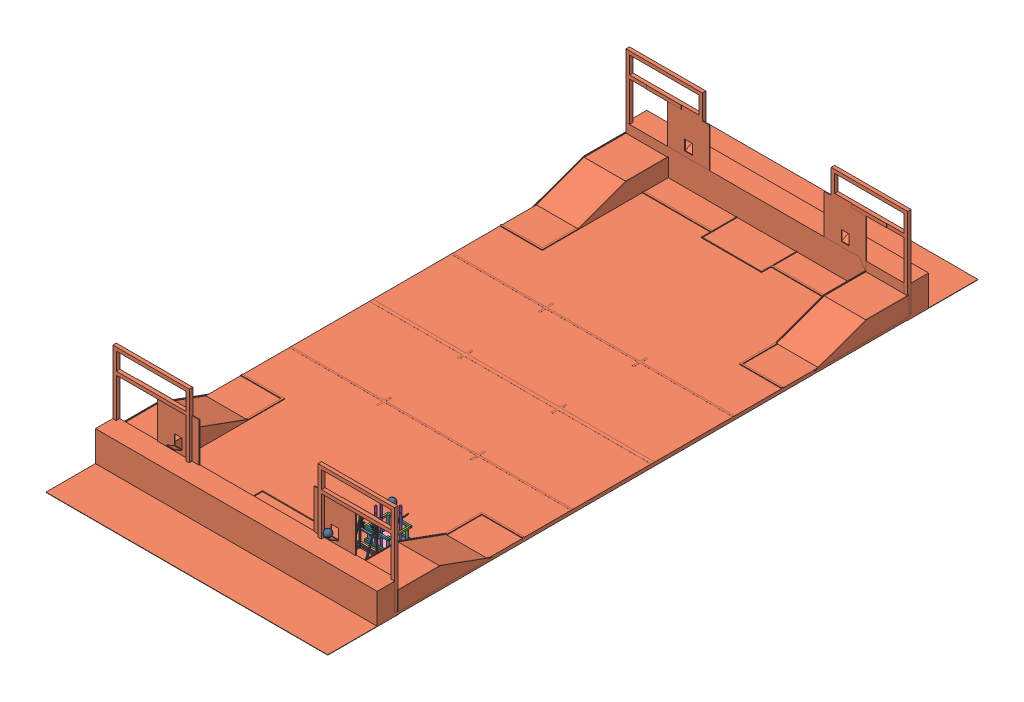
SolidWorks assembly Field, configuration Default. Lengths in mm.
Overall size (8136 2710 18688.65).
71 component instances, 20 part files, 5 mates.
Components (placement in the parent):
- Frame-1: Frame [Default] at (2713.2899 442.2211 10367.8073) x (1 0 0) z (0 -0.012665 0.99992) size (953.99 1281.22 1971.68)
  - User Library-C channel_-1: User Library-C channel_ [Default] at (-264.0117 419.6304 601.8198) size (760 31.75 28.57)
  - User Library-C channel_-2: User Library-C channel_ [Default] at (612.1433 419.6304 689.3998) x (0 0 -1) z (1 0 0) size (760 31.75 28.57)
  - User Library-C channel_-3: User Library-C channel_ [Default] at (463.4933 436.9764 689.3998) x (0 0 -1) z (-1 0 0) size (760 31.75 28.57)
  - User Library-C channel_-4: User Library-C channel_ [Default] at (-154.2067 419.6304 -296.5602) x (0 0 1) z (-1 0 0) size (760 31.75 28.57)
  - User Library-C channel_-5: User Library-C channel_ [Default] at (721.9484 419.6304 -208.9802) x (-1 0 0) z (0 0 -1) size (760 31.75 28.57)
  - User Library-C channel_-6: User Library-C channel_ [Default] at (-5.5567 419.6304 689.3998) x (0 0 -1) z (1 0 0) size (760 31.75 28.57)
  - Bumper-1: Bumper [Default] at (445.2766 -8.8291 392.6865) x (-1 0 0) z (0 0 -1) size (760 148.52 90.64)
    - Wood-1: Wood [Default] at (216.3082 417.3321 604.8417) size (760 125 15)
    - Foam-1: Foam [Default] at (-163.6918 447.7174 651.5917) x (0 -0.363902 0.931437) z (1 0 0) size (63.5 63.5 760)
    - Foam-3: Foam [Default] at (-163.6918 384.2174 651.5917) x (0 0.840256 0.542191) z (1 0 0) size (63.5 63.5 760)
  - cart-1: cart [Default] at (273.0164 410.445 -685.3291) x (1 0 0) z (0 0.012665 0.99992) size (690 1266.2 920.66)
    - cart plate-1: cart plate [Default] at (0 27 0) size (690 18 690)
    - 4.5x4.5 l=40cm-1: 4.5x4.5 l=40cm [Default] at origin size (45 373 45)
    - 4.5x4.5 l=40cm-2: 4.5x4.5 l=40cm [Default] x (0 0 -1) z (1 0 0) size (45 373 45)
    - 4.5x4.5 l=40cm-3: 4.5x4.5 l=40cm [Default] x (-1 0 0) z (0 0 -1) size (45 373 45)
    - 4.5x4.5 l=40cm-4: 4.5x4.5 l=40cm [Default] x (0 0 1) z (-1 0 0) size (45 373 45)
    - 4.5x4.5 l=68cm-1: 4.5x4.5 l=68cm [Default] at origin size (680 45 45)
    - 4.5x4.5 l=59cm-1: 4.5x4.5 l=59cm [Default] at origin size (45 45 590)
    - 4.5x4.5 l=68cm-2: 4.5x4.5 l=68cm [Default] x (-1 0 0) z (0 0 -1) size (680 45 45)
    - 4.5x4.5 l=59cm-2: 4.5x4.5 l=59cm [Default] x (-1 0 0) z (0 0 -1) size (45 45 590)
    - 4.5x4.5 l=68cm-3: 4.5x4.5 l=68cm [Default] at (0 -328 0) size (680 45 45)
    - 4.5x4.5 l=59cm-3: 4.5x4.5 l=59cm [Default] at (0 -328 0) size (45 45 590)
    - 4.5x4.5 l=68cm-4: 4.5x4.5 l=68cm [Default] at (0 -328 0) x (-1 0 0) z (0 0 -1) size (680 45 45)
    - 4.5x4.5 l=59cm-4: 4.5x4.5 l=59cm [Default] at (0 -328 0) x (-1 0 0) z (0 0 -1) size (45 45 590)
    - pvc pipe l=80cm-1: pvc pipe l=80cm [Default] at origin size (50.8 773 50.8)
    - pvc pipe l=80cm-2: pvc pipe l=80cm [Default] at (0 0 166.667) size (50.8 773 50.8)
    - pvc pipe l=80cm-3: pvc pipe l=80cm [Default] x (0 0 -1) z (1 0 0) size (50.8 773 50.8)
    - pvc pipe l=80cm-4: pvc pipe l=80cm [Default] at (166.667 0 0) x (0 0 -1) z (1 0 0) size (50.8 773 50.8)
    - pvc pipe l=80cm-5: pvc pipe l=80cm [Default] x (-1 0 0) z (0 0 -1) size (50.8 773 50.8)
    - pvc pipe l=80cm-6: pvc pipe l=80cm [Default] at (0 0 -166.667) x (-1 0 0) z (0 0 -1) size (50.8 773 50.8)
    - pvc pipe l=80cm-7: pvc pipe l=80cm [Default] x (0 0 1) z (-1 0 0) size (50.8 773 50.8)
    - pvc pipe l=80cm-8: pvc pipe l=80cm [Default] at (-166.667 0 0) x (0 0 1) z (-1 0 0) size (50.8 773 50.8)
    - crazy wheel-1: crazy wheel [Default] at (185 27 -185) size (60 101 80)
    - crazy wheel-2: crazy wheel [Default] at (185 27 185) size (60 101 80)
    - crazy wheel-3: crazy wheel [Default] at (-185 27 -185) size (60 101 80)
    - crazy wheel-4: crazy wheel [Default] at (-185 27 185) size (60 101 80)
    - Ball-1: Ball [Default] at (140.5737 1092.1977 28.2994) size (200 200 200)
    - F hand-1: F hand [Default] at (19.9991 445.2193 -490.7705) x (0.050393 0 0.998729) z (-0.998729 0 0.050393) size (342.75 87.22 10)
  - Handz-1: Handz [Default] at (871.8955 360.1229 416.4017) x (-1 0 0) z (0 0 -1) size (522.3 925.5 40)
    - 8020-30-3030-30-3030 X 4 M-1: 8020-30-3030-30-3030 X 4 M [Default] at (110.6415 -3045.9445 556.6015) size (30 870 30)
    - 8020-30-3030-30-3030 X 4 M-2: 8020-30-3030-30-3030 X 4 M [Default] at (600.5416 -3045.9445 556.6015) size (30 870 30)
    - Poygal-1: Poygal [Default] at (904.0582 509.5555 609.9819) x (0 0 -1) z (1 0 0) size (10 500 522.3)
  - hands of Handz-1: hands of Handz [Default] at (228.9435 878.3581 -175.0963) x (-1 0 0) z (0 0.946509 0.322676) size (736.72 654.9 627.14)
    - F holder-1: F holder [Default] at origin size (620 192.99 40)
    - F-Hand Complete-1: F-Hand Complete [Default] at (-42.5204 176.6839 360.2114) x (-0.161759 -0.38426 -0.908944) z (-0.935098 -0.234623 0.265601) size (552.85 473.7 180)
      - C-base 34cm-1: C-base 34cm [Default] at (956.6526 -166.43 -81.5617) x (-0.908944 0.321368 0.265601) z (-0.38426 -0.892915 -0.234623) size (444.34 31.75 28.57)
      - C-channel6cm-1: C-channel6cm [Default] at (-132.7439 -581.215 -32.979) x (0.38426 0.892915 0.234623) z (-0.908944 0.321368 0.265601) size (444.34 31.75 28.57)
      - C-Channel 4cm-1: C-Channel 4cm [Default] at (-5.5514 -640.6374 -93.5688) x (0.38426 0.892915 0.234623) z (0.908944 -0.321368 -0.265601) size (444.34 31.75 28.57)
      - Holder-1: Holder [Default] at (208.6091 126.4129 137.339) x (-0.161759 0.315319 -0.935098) z (0.38426 0.892915 0.234623) size (31.8 150.5 40)
    - F-Hand Complete-2: F-Hand Complete [Default] at (287.0891 176.6839 360.2114) x (-0.161759 -0.38426 -0.908944) z (-0.935098 -0.234623 0.265601) size (552.85 473.7 180)
      - C-base 34cm-1: C-base 34cm [Default] at (956.6526 -166.43 -81.5617) x (-0.908944 0.321368 0.265601) z (-0.38426 -0.892915 -0.234623) size (444.34 31.75 28.57)
      - C-channel6cm-1: C-channel6cm [Default] at (-132.7439 -581.215 -32.979) x (0.38426 0.892915 0.234623) z (-0.908944 0.321368 0.265601) size (444.34 31.75 28.57)
      - C-Channel 4cm-1: C-Channel 4cm [Default] at (-5.5514 -640.6374 -93.5688) x (0.38426 0.892915 0.234623) z (0.908944 -0.321368 -0.265601) size (444.34 31.75 28.57)
      - Holder-1: Holder [Default] at (208.6091 126.4129 137.339) x (-0.161759 0.315319 -0.935098) z (0.38426 0.892915 0.234623) size (31.8 150.5 40)
  - C channel 85cm-1: C channel 85cm [Default] at (453.1403 413.8026 149.4239) x (-0.001602 0.934593 -0.355716) z (0 0.355716 0.934594) size (858 31.75 28.57)
  - C channel 85cm-2: C channel 85cm [Default] at (22.1414 413.7753 152.7057) x (0.001661 0.934593 -0.355716) z (0 0.355716 0.934594) size (858 31.75 28.57)
  - Bumper-2: Bumper [Default] at (12.6601 -14.6329 0.1532) size (760 148.52 90.64)
    - Wood-1: Wood [Default] at (216.3082 417.3321 604.8417) size (760 125 15)
    - Foam-1: Foam [Default] at (-163.6918 447.7174 651.5917) x (0 -0.363902 0.931437) z (1 0 0) size (63.5 63.5 760)
    - Foam-3: Foam [Default] at (-163.6918 384.2174 651.5917) x (0 0.840256 0.542191) z (1 0 0) size (63.5 63.5 760)
  - Bumper-3: Bumper [Default] at (10.4767 -5.9823 412.728) x (0 0 -1) z (1 0 0) size (760 148.52 90.64)
    - Wood-1: Wood [Default] at (216.3082 417.3321 604.8417) size (760 125 15)
    - Foam-1: Foam [Default] at (-163.6918 447.7174 651.5917) x (0 -0.363902 0.931437) z (1 0 0) size (63.5 63.5 760)
    - Foam-3: Foam [Default] at (-163.6918 384.2174 651.5917) x (0 0.840256 0.542191) z (1 0 0) size (63.5 63.5 760)
  - Bumper-4: Bumper [Default] at (447.46 -7.1738 -19.8884) x (0 0 1) z (-1 0 0) size (760 148.52 90.64)
    - Wood-1: Wood [Default] at (216.3082 417.3321 604.8417) size (760 125 15)
    - Foam-1: Foam [Default] at (-163.6918 447.7174 651.5917) x (0 -0.363902 0.931437) z (1 0 0) size (63.5 63.5 760)
    - Foam-3: Foam [Default] at (-163.6918 384.2174 651.5917) x (0 0.840256 0.542191) z (1 0 0) size (63.5 63.5 760)
- field-1: field [Default] at (690.1931 786.3133 3832.4101) size (8136 2710 18688.65)
- Ball-1: Ball [Default] at (2936.4397 1909.0833 11368.147) x (0.989308 -0.050656 0.136762) z (-0.138561 -0.033874 0.989774) size (200 200 200)
Mates (geometry in assembly coordinates):
- Tangent1: tangent: cylinder of Frame-1/cart-1/crazy wheel-4 through (2801.3062 824.8133 9885.2316) axis (1 0 0) radius 37.5; plane of field-1 through (690.1931 787.3133 170.2476) normal (0 1 0)
- Tangent2: tangent: cylinder of Frame-1/cart-1/crazy wheel-3 through (2801.3062 824.8133 9515.2316) axis (1 0 0) radius 37.5; plane of field-1 through (690.1931 787.3133 7494.5726) normal (0 1 0)
- Tangent3: tangent: cylinder of Frame-1/cart-1/crazy wheel-1 through (3171.3062 824.8133 9515.2316) axis (1 0 0) radius 37.5; plane of field-1 through (690.1931 787.3133 7494.5726) normal (0 1 0)
- Tangent4: tangent: cylinder of Frame-1/cart-1/crazy wheel-2 through (3171.3062 824.8133 9885.2316) axis (1 0 0) radius 37.5; plane of field-1 through (690.1931 787.3133 7494.5726) normal (0 1 0)
- Distance1: distance = 100 mm: cylinder of Frame-1/Bumper-2/Foam-1 through (3322.2582 867.0163 11024.9851) axis (-1 0 0) radius 31.75; plane of field-1 through (4740.1931 686.3133 11156.7351) normal (0 0 -1)
